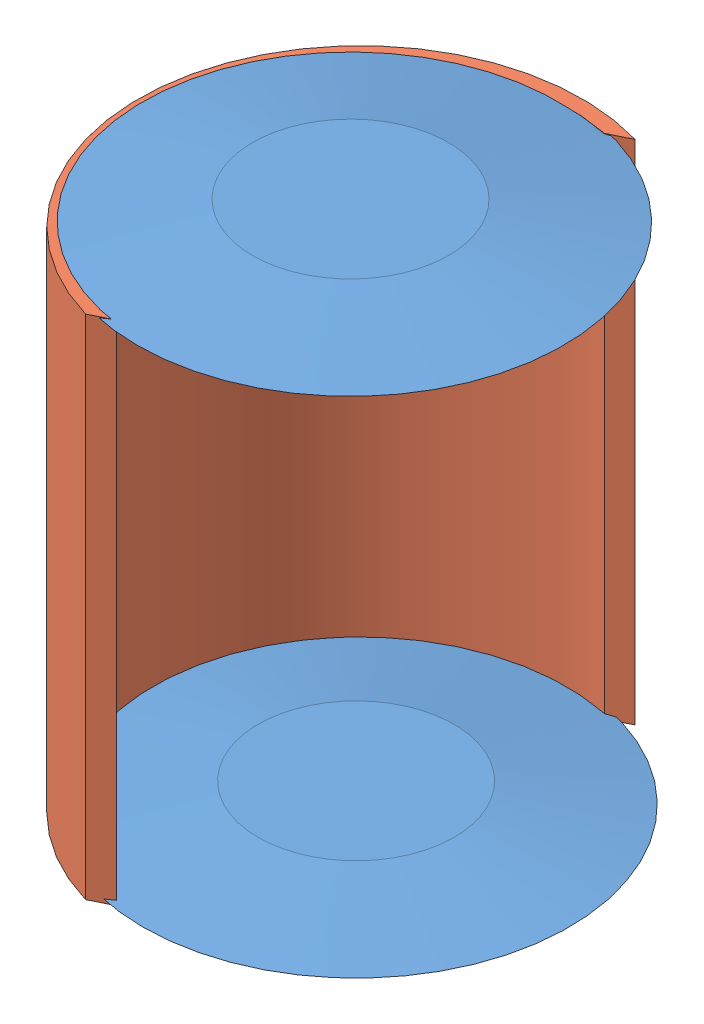
SolidWorks assembly Ensamblaje1, configuration Predeterminado. Lengths in mm.
Overall size (53.86 65.92 54.48).
3 component instances, 2 part files, 0 mates.
Components (placement in the parent):
- base_canasta-1: base_canasta [Predeterminado] at (-0.4275 -7.0675 53.34) size (53.34 2.54 53.34)
- pared_canasta-1: pared_canasta [Predeterminado] at (0.2563 -7.5267 53.4848) size (35.5 63.5 54.44)
- base_canasta-3: base_canasta [Predeterminado] at (-0.9432 55.8509 53.5226) size (53.34 2.54 53.34)
